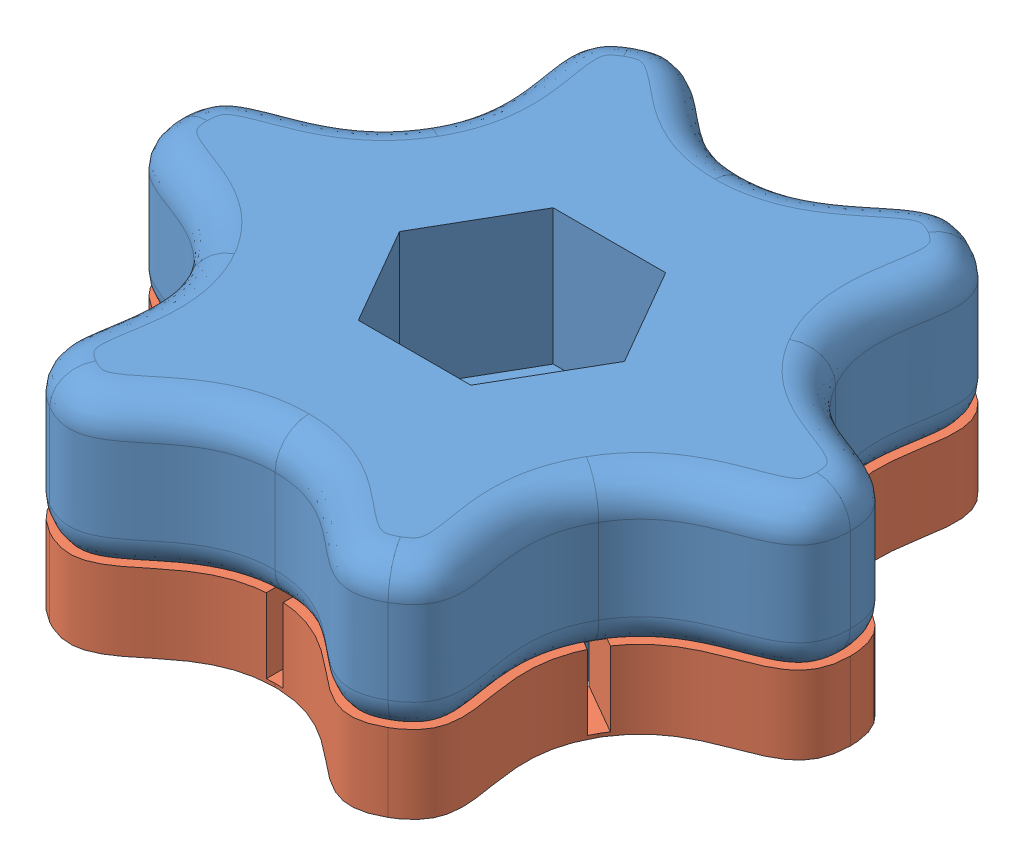
SolidWorks assembly BoltKnobWSupport, configuration Default. Lengths in mm.
Overall size (41.74 13 37.39).
2 component instances, 2 part files, 0 mates.
Components (placement in the parent):
- BoltKnob-1: BoltKnob [Default] at (19.0858 27.2185 28.4443) size (41.74 13 37.39)
- Support^BoltKnobWSupport-1: Support^BoltKnobWSupport [Default] at origin size (40.03 4.71 36.85) (virtual)
